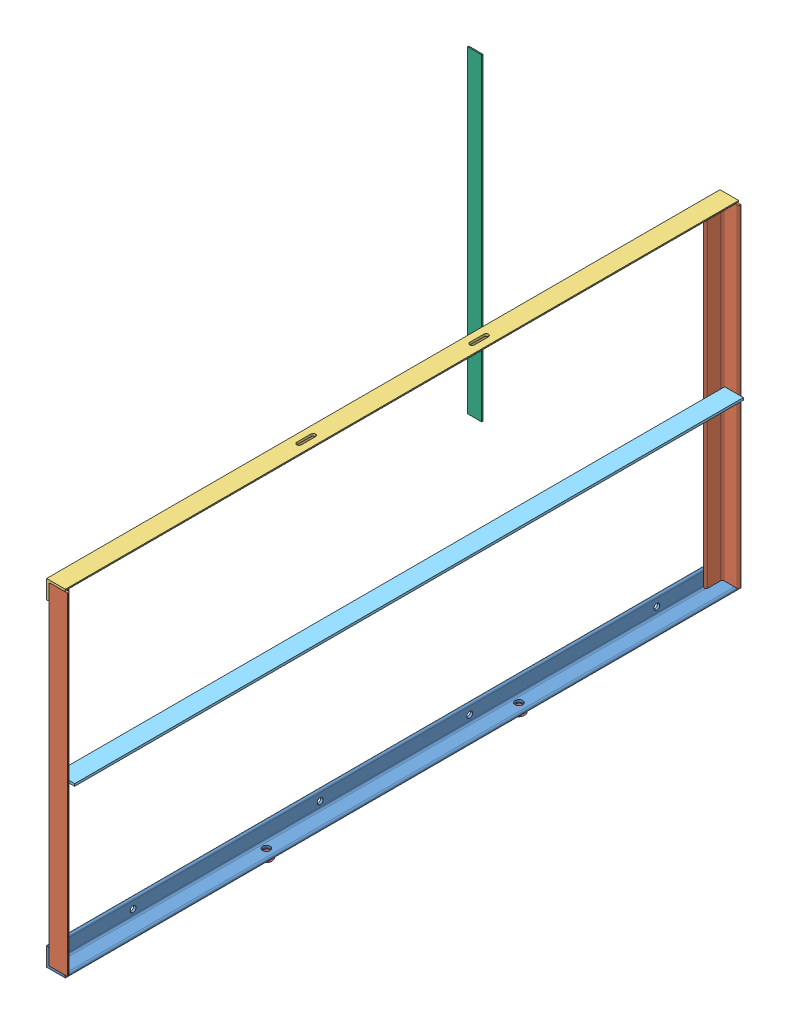
SolidWorks assembly 01-070-00-0_2, configuration Default. Lengths in mm.
Overall size (755.29 931.29 1831.97).
8 component instances, 6 part files, 20 mates.
Components (placement in the parent):
- 01-068-00-0-4: 01-068-00-0 [Default] at origin size (50.8 50.8 1828.8)
- 01-069-00-0-1: 01-069-00-0 [Default] at (6.35 457.2 914.4) x (1 0 0) z (0 1 0) size (50.8 50.8 901.7)
- 01-069-00-0-5: 01-069-00-0 [Default] at (6.35 457.2 -914.4) x (1 0 0) z (0 -1 0) size (50.8 50.8 901.7)
- 01-086-00-0-3: 01-086-00-0 [Default] at (0 914.4 0) x (1 0 0) z (0 0 -1) size (50.8 50.8 1828.8)
- hex nut_ai-1: hex nut_ai [HNUT 0.7500-10-D-C] at (25.4 -16.891 -342.9) x (1 0 0) z (0 -1 0) size (28.57 33 16.89)
- hex nut_ai-2: hex nut_ai [HNUT 0.7500-10-D-C] at (25.4 -16.891 342.9) x (1 0 0) z (0 -1 0) size (28.57 33 16.89)
- 01-118-00-0-1: 01-118-00-0 [Default] at (19.05 457.2 -908.05) x (0 0 1) z (-1 0 0) size (1816.1 6.35 50.8)
- New Grate Bar-1: New Grate Bar [Default] at (-685.4391 44.45 -914.4) x (0 0 -1) z (0 -1 0) size (3.17 38.1 863.6)
Mates (geometry in assembly coordinates):
- Coincident19: coincident aligned: plane of 01-068-00-0-4 through (0 0 0) normal (0 0 1); plane of assembly through (0 0 0) normal (0 0 1)
- Coincident20: coincident aligned: plane of 01-068-00-0-4 through (0 0 0) normal (1 0 0); plane of assembly through (0 0 0) normal (1 0 0)
- Coincident21: coincident aligned: plane of 01-068-00-0-4 through (0 0 0) normal (0 1 0); plane of assembly through (0 0 0) normal (0 1 0)
- Coincident30: coincident anti-aligned: plane of 01-068-00-0-4 through (50.8 0 914.4) normal (0 -1 0); plane of hex nut_ai-1 through (25.4 0 -326.4022) normal (0 1 0)
- Concentric1: concentric aligned: circle of 01-068-00-0-4; circle of hex nut_ai-1
- Coincident32: coincident anti-aligned: plane of 01-068-00-0-4 through (50.8 0 914.4) normal (0 -1 0); plane of hex nut_ai-2 through (25.4 0 359.3978) normal (0 1 0)
- Concentric2: concentric aligned: cylinder of 01-068-00-0-4 through (25.4 0 342.9) axis (0 -1 0) radius 10.3187; circle of hex nut_ai-2
- Coincident35: coincident anti-aligned: plane of 01-068-00-0-4 through (6.35 46.0426 914.4) normal (1 0 0); plane of 01-069-00-0-5 through (6.35 6.35 -914.4) normal (-1 0 0)
- Coincident36: coincident aligned: plane of 01-068-00-0-4 through (1.5926 46.0426 -914.4) normal (0 0 -1); plane of 01-069-00-0-5 through (57.15 6.35 -914.4) normal (0 0 -1)
- Coincident37: coincident anti-aligned: plane of 01-068-00-0-4 through (11.1125 6.35 914.4) normal (0 1 0); plane of 01-069-00-0-5 through (7.9426 6.35 -868.3574) normal (0 -1 0)
- Coincident38: coincident anti-aligned: plane of 01-068-00-0-4 through (6.35 46.0426 914.4) normal (1 0 0); plane of 01-069-00-0-1 through (6.35 908.05 914.4) normal (-1 0 0)
- Coincident39: coincident anti-aligned: plane of 01-068-00-0-4 through (11.1125 6.35 914.4) normal (0 1 0); plane of 01-069-00-0-1 through (7.9426 6.35 868.3574) normal (0 -1 0)
- Coincident41: coincident anti-aligned: plane of 01-069-00-0-1 through (7.9426 908.05 868.3574) normal (0 1 0); plane of 01-086-00-0-3 through (11.1125 908.05 -914.4) normal (0 -1 0)
- Coincident43: coincident aligned: plane of 01-068-00-0-4 through (0 0 914.4) normal (-1 0 0); plane of 01-086-00-0-3 through (0 914.4 -914.4) normal (-1 0 0)
- Coincident44: coincident aligned: plane of 01-068-00-0-4 through (1.5926 46.0426 914.4) normal (0 0 1); plane of 01-086-00-0-3 through (1.5926 868.3574 914.4) normal (0 0 1)
- Distance5: distance = 12.7 mm anti-aligned: plane of 01-118-00-0-1 through (19.05 463.55 -908.05) normal (-1 0 0); plane of 01-068-00-0-4 through (6.35 46.0426 914.4) normal (1 0 0)
- Distance6: distance = 457.2 mm aligned: plane of 01-118-00-0-1 through (69.85 457.2 -908.05) normal (0 -1 0); plane of 01-068-00-0-4 through (50.8 0 914.4) normal (0 -1 0)
- Coincident52: coincident anti-aligned: plane of 01-069-00-0-1 through (17.4625 908.05 908.05) normal (0 0 -1); plane of 01-118-00-0-1 through (19.05 463.55 908.05) normal (0 0 1)
- Coincident53: coincident anti-aligned: plane of 01-069-00-0-5 through (57.15 6.35 -914.4) normal (0 0 -1); plane of New Grate Bar-1 through (216.2609 177.5102 -914.4) normal (0 0 1)
- Coincident57: coincident anti-aligned: plane of 01-086-00-0-3 through (11.1125 908.05 -914.4) normal (0 -1 0); plane of New Grate Bar-1 through (-647.3391 908.05 -914.4) normal (0 1 0)
